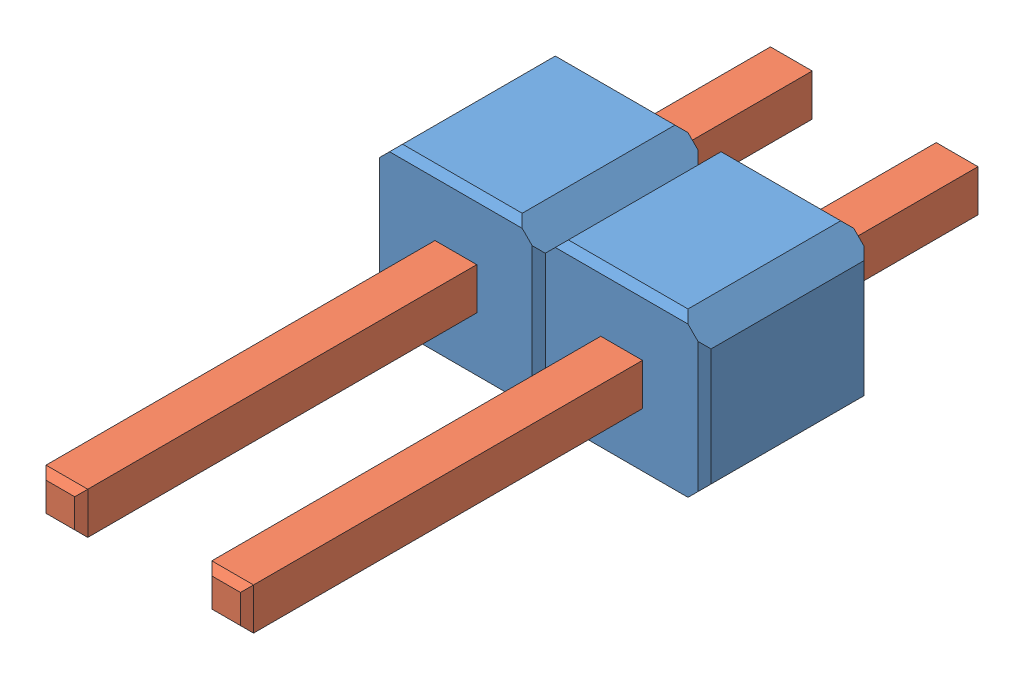
SolidWorks assembly Сборка11, configuration Default. Lengths in mm.
Overall size (5.08 2.5 11.3).
6 component instances, 2 part files, 2 mates.
Components (placement in the parent):
- pls_1_vert-1: pls_1_vert [Default] at (2.4589 -1.2488 -2.1291) size (2.54 2.5 11.3)
  - pin_plastic-1: pin_plastic [По умолчанию] at (1.6831 0.6372 -1.2507) size (2.54 2.5 2.54)
  - pin-1: pin [Default] at (-0.8569 0.6372 7.3493) x (1 0 0) z (0 1 0) size (0.64 11.3 0.64)
- pls_1_vert-2: pls_1_vert [Default] at (-0.0811 -1.2488 -2.1291) size (2.54 2.5 11.3)
  - pin_plastic-1: pin_plastic [По умолчанию] at (1.6831 0.6372 -1.2507) size (2.54 2.5 2.54)
  - pin-1: pin [Default] at (-0.8569 0.6372 7.3493) x (1 0 0) z (0 1 0) size (0.64 11.3 0.64)
Mates (geometry in assembly coordinates):
- Совпадение1: coincident: line of pls_1_vert-1/pin_plastic-1 through (0.332 -1.5081 -0.9398) axis (0 1 0); line of pls_1_vert-2/pin_plastic-1 through (0.332 0.2848 -0.9398) axis (0 -1 0)
- Совпадение2: coincident aligned: line of pls_1_vert-1/pin_plastic-1 through (0.332 0.2848 -0.9398) axis (0 0 -1); line of pls_1_vert-2/pin_plastic-1 through (0.332 0.2848 -0.9398) axis (0 0 -1)
